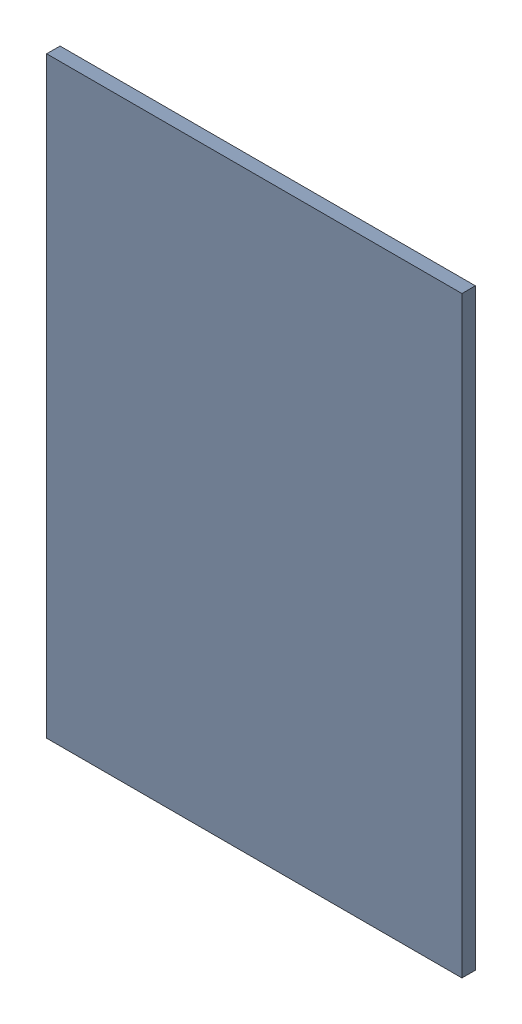
SolidWorks assembly Pad C3-2(27.19mm,48.5mm) on Top Layer, configuration Predeterminado. Lengths in mm.
Overall size (1.1 1.57 0.04).
2 component instances, 1 part files, 0 mates.
Components (placement in the parent):
- Pad C3-2(27.19mm,48.5mm) on Top Layer-1-1: Pad C3-2(27.19mm,48.5mm) on Top Layer-1 [Predeterminado] at (-68.317 -44.187 -0.0457) size (1.1 1.57 0.04)
  - Pad C3-2(27.19mm,48.5mm) on Top Layer-Part-1-1: Pad C3-2(27.19mm,48.5mm) on Top Layer-Part-1 [Predeterminado] at origin size (1.1 1.57 0.04)
